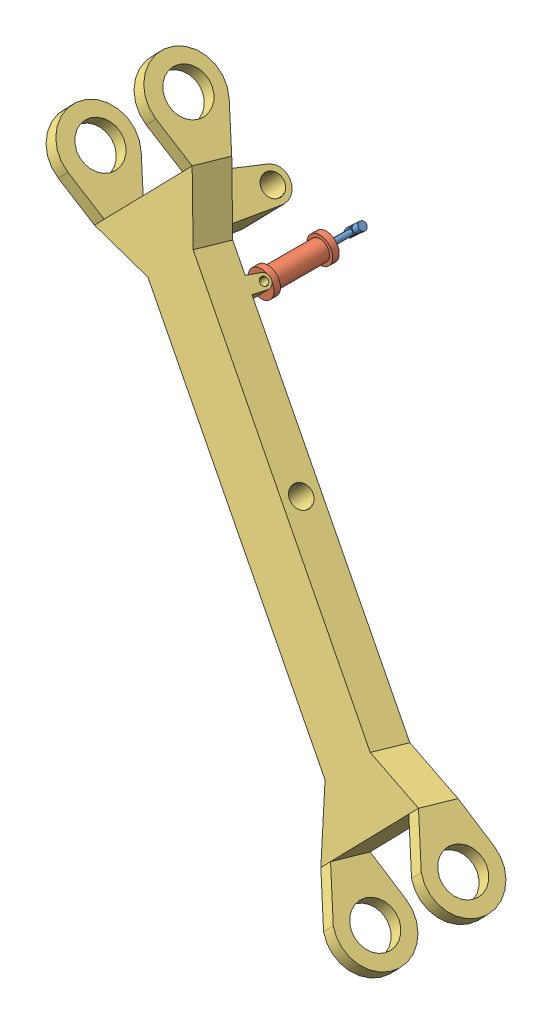
SolidWorks assembly Assem1, configuration Default. Lengths in mm.
Overall size (830.3 816.73 425.52).
3 component instances, 3 part files, 5 mates.
Components (placement in the parent):
- nasos 2 malenkyi-1: nasos 2 malenkyi [Default] at (-72.6084 13.9664 36.6514) x (-0.733485 -0.679706 -0.000092) z (-0.001299 0.001267 0.999998) size (26.25 15 131.44)
- nasos malenkyi-1: nasos malenkyi [Default] at (-72.9663 14.3154 312.2021) x (0.698149 0.715952 0) z (-0.001299 0.001267 0.999998) size (37.5 37.5 131.25)
- hinge2-1: hinge2 [Default] at (195.9066 -8.3508 504.3309) x (0.696514 -0.679195 0.231435) z (-0.698149 -0.715952 0) size (949.73 170.92 201.22)
Mates (geometry in assembly coordinates):
- Concentric1: concentric anti-aligned: cylinder of nasos 2 malenkyi-1 through (-73.0242 14.3719 356.7623) axis (0.001299 -0.001267 -0.999998) radius 3.75; cylinder of nasos malenkyi-1 through (-72.9454 14.295 296.0749) axis (-0.001299 0.001267 0.999998) radius 4.5
- LimitDistance1: limit distance = 1 mm anti-aligned: plane of nasos 2 malenkyi-1 through (-73.0415 14.3887 370.0748) normal (-0.001299 0.001267 0.999998); plane of nasos malenkyi-1 through (-73.0428 14.39 371.0748) normal (0.001299 -0.001267 -0.999998)
- LimitDistance2: limit distance = 60.6875 mm anti-aligned: plane of nasos 2 malenkyi-1 through (-73.0242 14.3719 356.7623) normal (0.001299 -0.001267 -0.999998); plane of nasos malenkyi-1 through (-72.9454 14.295 296.0749) normal (-0.001299 0.001267 0.999998)
- Concentric2: concentric anti-aligned: cylinder of nasos malenkyi-1 through (-86.1818 1.0134 408.5748) axis (0.698149 0.715952 0) radius 5.625; cylinder of hinge2-1 through (-13.3185 75.7347 408.5748) axis (-0.698149 -0.715952 0) radius 5.625
- Coincident5: coincident anti-aligned: plane of nasos malenkyi-1 through (-55.5846 10.4603 286.7273) normal (0.698149 0.715952 0); plane of hinge2-1 through (-85.7059 39.8327 389.8872) normal (-0.698149 -0.715952 0)
